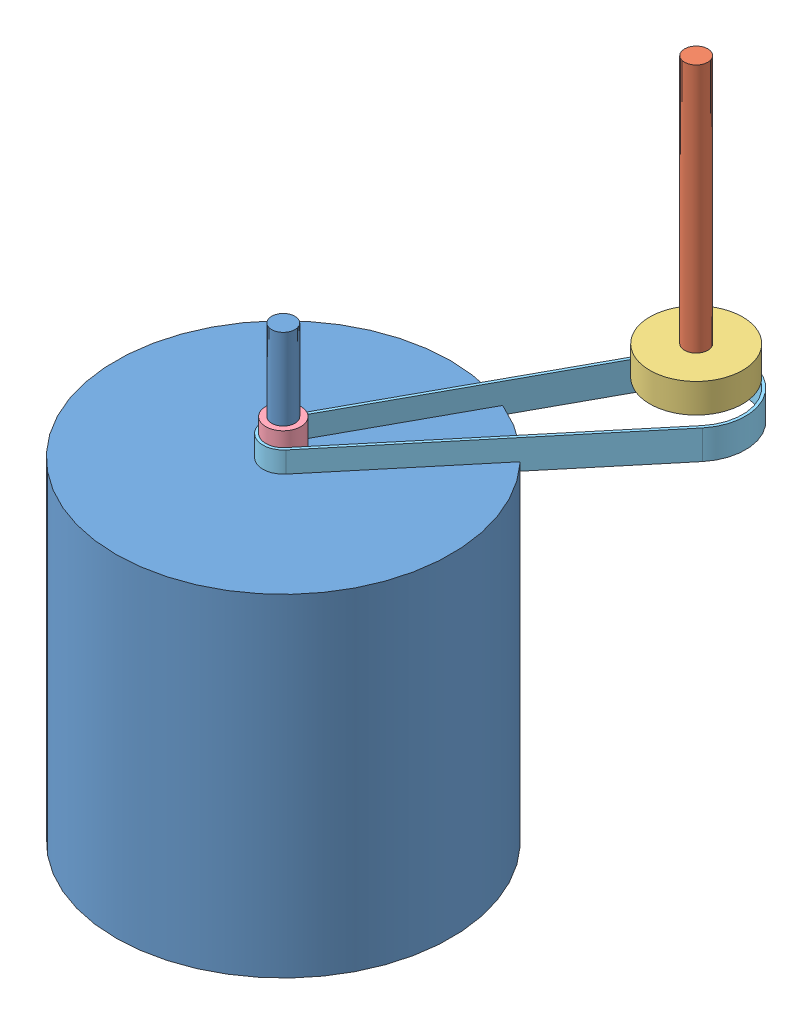
SolidWorks assembly Courroie, configuration Défaut. Lengths in mm.
Overall size (131.71 219.93 158.75).
5 component instances, 5 part files, 3 mates.
Components (placement in the parent):
- PoteurBlender-1: PoteurBlender [Défaut] at (-13.0413 35.8615 154) size (115 154 115)
- Axe-1: Axe [Défaut] at (10.2985 41.7879 69.65) x (1 0 0) z (0 1 0) size (8 8 100)
- PoulieLarge-1: PoulieLarge [Défaut] at (5.9686 46.19 94.4629) x (0.9999 0 0.014148) z (0 1 0) size (31.8 31.8 10)
- PoulieFine-1: PoulieFine [Défaut] at (-22.7964 38.0448 167.8972) x (0.063825 0 -0.997961) z (0 1 0) size (12 12 10)
- Courroie1-6-1: Courroie1-6 [Défaut] at (-13.0413 43.0448 154) x (1 0 0) z (0 -1 0) size (81.21 108.25 10)
Mates (geometry in assembly coordinates):
- Coaxiale2: concentric: cylinder of PoteurBlender-1 through (-13.0413 75.8615 154) axis (0 -1 0) radius 4; cylinder of PoulieFine-1 through (-13.0413 48.0448 154) axis (0 -1 0) radius 4
- Coaxiale3: concentric: cylinder of Axe-1 through (44.2683 141.7879 69.65) axis (0 -1 0) radius 4; cylinder of PoulieLarge-1 through (44.2683 56.19 69.65) axis (0 -1 0) radius 4
- Contrainte de courroie1: belt = 31.8 : 12 mm: cylinder of PoulieFine-1 through (-13.0413 48.0448 154) axis (0 -1 0) radius 6; cylinder of PoulieLarge-1 through (44.2683 56.19 69.65) axis (0 -1 0) radius 15.9; line of assembly; line of assembly; line of Courroie1-6-1; line of Courroie1-6-1
